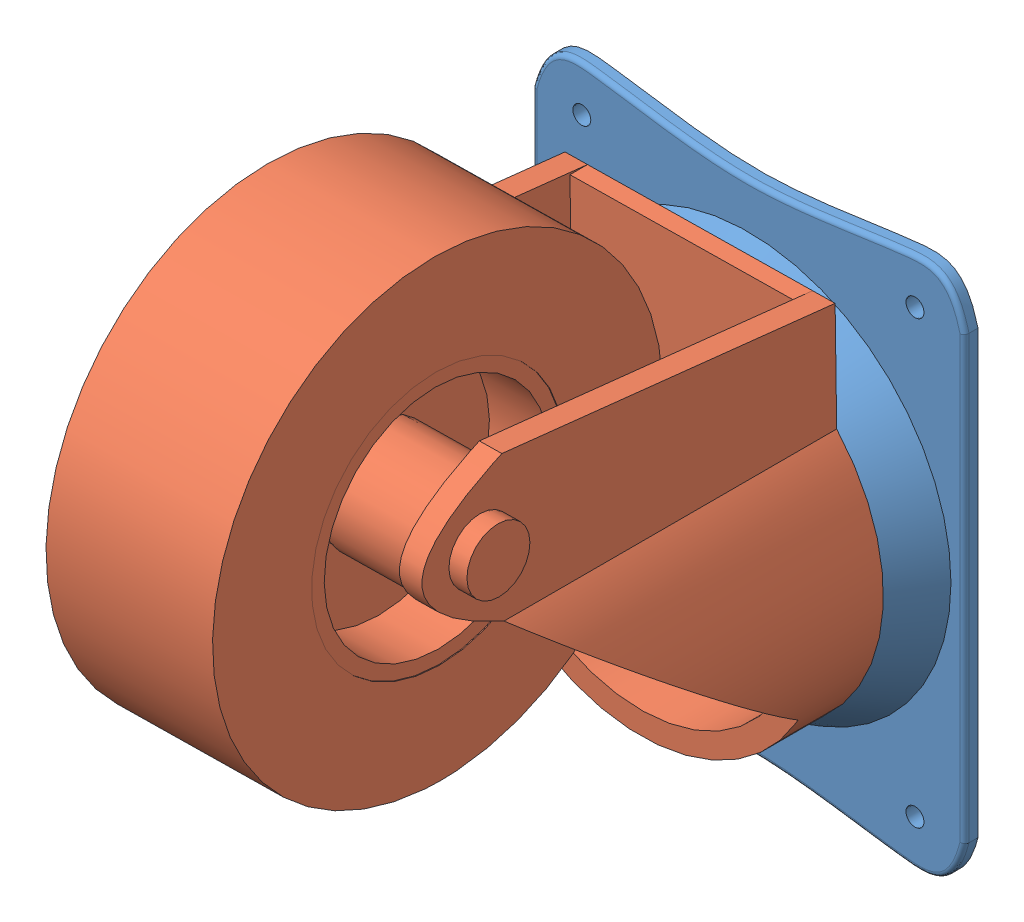
SolidWorks assembly Old Caster Wheel and Base, configuration Default. Lengths in mm.
Overall size (51.72 77.87 71.06).
2 component instances, 2 part files, 2 mates.
Components (placement in the parent):
- Old Caster Wheel Base-1: Old Caster Wheel Base [Default] at (-44.3298 4.6716 -4.8195) size (51.72 62.34 11.36)
- Caster Wheel-1: Caster Wheel [Default] at (-44.3298 4.6716 1.6805) x (0.999894 0.014576 0) z (0 0 1) size (40 66.23 63.7)
Mates (geometry in assembly coordinates):
- Concentric1: concentric aligned: cylinder of Old Caster Wheel Base-1 through (-44.3298 4.6716 3.6805) axis (0 0 -1) radius 7.5; cylinder of Caster Wheel-1 through (-44.3298 4.6716 3.6305) axis (0 0 -1) radius 7.5
- Coincident1: coincident anti-aligned: plane of Old Caster Wheel Base-1 through (-44.3298 4.6716 1.6805) normal (0 0 1); plane of Caster Wheel-1 through (-44.3298 4.6716 1.6805) normal (0 0 -1)
